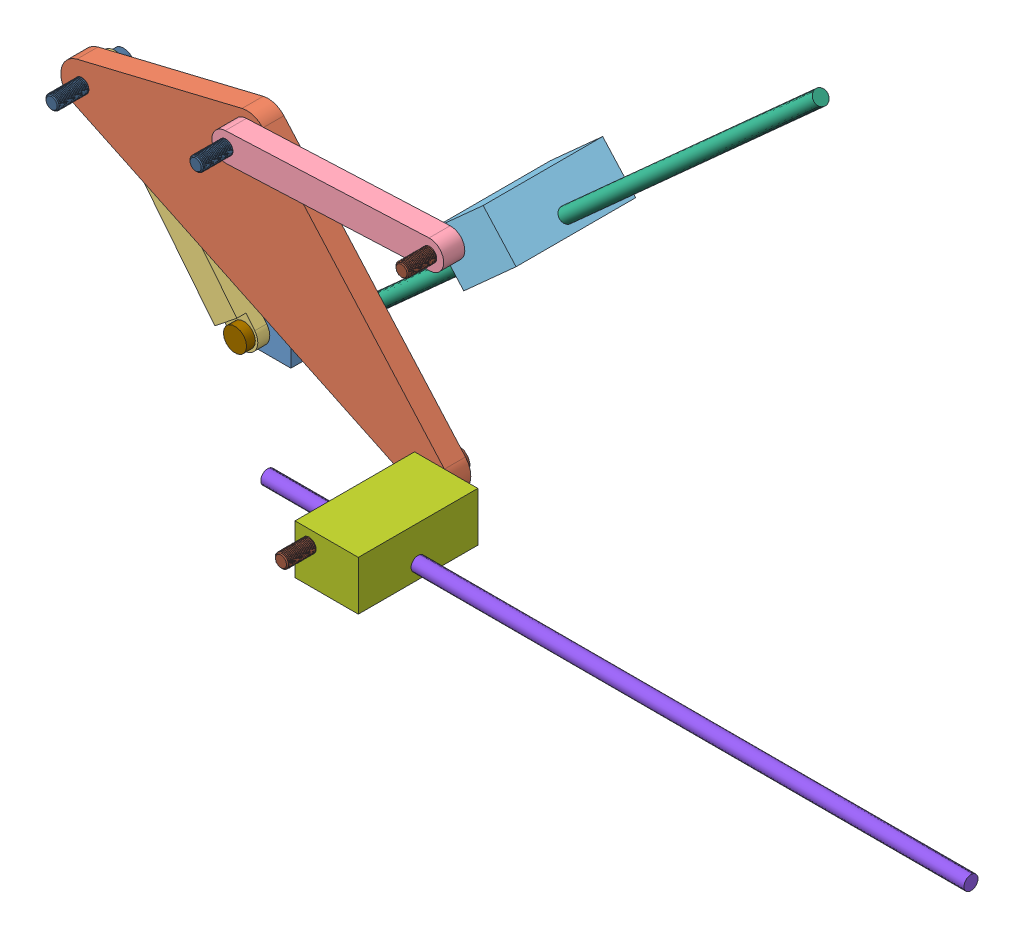
SolidWorks assembly sapr_5_Сборочная_деталь_1, configuration По умолчанию. Lengths in mm.
Overall size (1389.38 752.11 392.5).
13 component instances, 11 part files, 35 mates.
Components (placement in the parent):
- sapr_5_стойка_A-1: sapr_5_стойка_A [По умолчанию] at origin size (80 50 50)
- sapr_5_тело_BDC-1: sapr_5_тело_BDC [По умолчанию] at (305.885 0 70) x (0.903167 -0.42929 0) z (0 0 1) size (606 212.06 30)
- sapr_5_кривошип_AB-1: sapr_5_кривошип_AB [По умолчанию] at (0 0 40) x (0.624147 -0.781307 0) z (0 0 1) size (340 40 30)
- sapr_5_шатун_DE-1: sapr_5_шатун_DE [По умолчанию] at (337.3495 303.7509 100) x (0.99905 0.043571 0) z (0 0 1) size (330 40 30)
- Деталь5^sapr_5_Сборочная_деталь_1-1: Деталь5^sapr_5_Сборочная_деталь_1 [По умолчанию] at (-28.4092 649.8427 85) x (-0.758571 -0.651591 0) z (0 0 -1) size (101.61 72.32 170) (virtual)
- Деталь6^sapr_5_Сборочная_деталь_1-1: Деталь6^sapr_5_Сборочная_деталь_1 [По умолчанию] at (663.8765 593.5874 42.8641) x (-0.194708 0.216245 -0.956727) z (0.743145 0.669131 0) size (20 20 870) (virtual)
- Деталь7^sapr_5_Сборочная_деталь_1-1: Деталь7^sapr_5_Сборочная_деталь_1 [По умолчанию] at (-6298.3923 -94.2281 85) x (0.921199 -0.389093 0) z (0 0 1) size (110.14 99.5 170) (virtual)
- Деталь1^sapr_5_Сборочная_деталь_1-1: Деталь1^sapr_5_Сборочная_деталь_1 [По умолчанию] at (762.1607 -94.2281 85) x (0 0 -1) z (1 0 0) size (20 20 1000) (virtual)
- sapr_5_болт_A-1: sapr_5_болт_A [По умолчанию] at (0 0 42) x (-0.923728 -0.383049 0) z (0 0 -1) size (33 33 122.5)
- sapr_5_болт_B_и_D-1: sapr_5_болт_B_и_D [По умолчанию] at (-187.2441 234.3921 38) size (33 33 102.5)
- sapr_5_болт_B_и_D-2: sapr_5_болт_B_и_D [По умолчанию] at (47.6249 291.1153 68) x (0.967831 0.251601 0) z (0 0 1) size (33 33 102.5)
- sapr_5_болт_C_и_E-1: sapr_5_болт_C_и_E [По умолчанию] at (337.3495 303.7509 -85) size (33 33 252.5)
- sapr_5_болт_C_и_E-2: sapr_5_болт_C_и_E [По умолчанию] at (305.885 0 55) x (0.841902 0.53963 0) z (0 0 1) size (33 33 252.5)
Mates (geometry in assembly coordinates):
- Совпадение3: coordinate: point of sapr_5_стойка_A-1; point of assembly
- Концентричный1: concentric aligned: cylinder of sapr_5_стойка_A-1 through (0 0 25) axis (0 0 -1) radius 10; cylinder of sapr_5_кривошип_AB-1 through (0 0 55) axis (0 0 -1) radius 10
- Совпадение4: coincident anti-aligned: plane of sapr_5_стойка_A-1 through (0 0 25) normal (0 0 1); plane of sapr_5_кривошип_AB-1 through (0 0 25) normal (0 0 -1)
- Концентричный2: concentric aligned: cylinder of sapr_5_тело_BDC-1 through (-187.2441 234.3921 85) axis (0 0 -1) radius 10; cylinder of sapr_5_кривошип_AB-1 through (-187.2441 234.3921 55) axis (0 0 -1) radius 10
- На месте4: in place: plane of ? through (491.4763 205.3087 60) normal (0 0 1); plane of ? through (0 0 60) normal (0 0 1); moOrthogonalPlaneRef_w of ? through (491.4763 205.3087 60) normal (0 0 1); plane of ? through (0 0 60) normal (0 1 0); plane of ? through (491.4763 205.3087 60) normal (0 0 1); plane of ? through (0 0 60) normal (1 0 0); plane of ? through (491.4763 205.3087 60) normal (0 0 1); unknown of ?
- Совпадение21: coincident aligned: plane of sapr_5_тело_BDC-1; plane of Деталь7^sapr_5_Сборочная_деталь_1-1
- Совпадение22: coincident aligned: moOrthogonalPlaneRef_w of sapr_5_тело_BDC-1 through (836.1365 24.5996 60) normal (0.081391 0.996682 0); plane of Деталь7^sapr_5_Сборочная_деталь_1-1
- Совпадение23: coincident anti-aligned: moOrthogonalPlaneRef_w of sapr_5_тело_BDC-1 through (836.1365 24.5996 60) normal (-0.996682 0.081391 0); plane of Деталь7^sapr_5_Сборочная_деталь_1-1
- Совпадение24: coincident anti-aligned: plane of sapr_5_тело_BDC-1 through (515.9638 141.815 60) normal (0 0 1); plane of Деталь7^sapr_5_Сборочная_деталь_1-1 through (827.9654 -90.7821 60) normal (0 0 -1)
- Параллельность1: parallel anti-aligned: line of ? through (907.5887 -21.6191 100) axis (-1 0 0)
- Концентричный11: concentric anti-aligned: cylinder of sapr_5_шатун_DE-1 through (337.3495 303.7509 115) axis (0 0 -1) radius 10; cylinder of Деталь5^sapr_5_Сборочная_деталь_1-1 through (337.3495 303.7509 -85) axis (0 0 1) radius 10
- Совпадение26: coincident anti-aligned: plane of sapr_5_тело_BDC-1 through (47.6249 291.1153 85) normal (0 0 1); plane of Деталь7^sapr_5_Сборочная_деталь_1-1 through (-6298.3923 -94.2281 85) normal (0 0 -1)
- На месте5: in place: plane of ? through (762.1607 -50 100) normal (1 0 0); plane of ? through (762.1607 0 0) normal (1 0 0); plane of ? through (762.1607 -50 100) normal (1 0 0); plane of ? through (762.1607 0 0) normal (0 1 0); plane of ? through (762.1607 -50 100) normal (1 0 0); plane of ? through (762.1607 0 0) normal (0 0 -1); plane of ? through (762.1607 -50 100) normal (1 0 0); unknown of ?
- Совпадение28: coincident aligned: plane of Деталь7^sapr_5_Сборочная_деталь_1-1; plane of Деталь1^sapr_5_Сборочная_деталь_1-1
- Совпадение29: coincident aligned: moOrthogonalPlaneRef_w of Деталь7^sapr_5_Сборочная_деталь_1-1 through (762.1607 -122.7583 60) normal (0 1 0); plane of Деталь1^sapr_5_Сборочная_деталь_1-1 through (762.1607 -122.7583 60) normal (0 1 0)
- Совпадение30: coincident anti-aligned: moOrthogonalPlaneRef_w of Деталь7^sapr_5_Сборочная_деталь_1-1 through (762.1607 -122.7583 60) normal (0 0 1); plane of Деталь1^sapr_5_Сборочная_деталь_1-1 through (762.1607 -122.7583 60) normal (0 0 -1)
- Параллельность2: parallel aligned: cylinder of Деталь1^sapr_5_Сборочная_деталь_1-1 through (162.1607 -30 170) axis (1 0 0) radius 10; line of assembly
- Параллельность3: parallel aligned: cylinder of Деталь1^sapr_5_Сборочная_деталь_1-1 through (162.1607 -30 170) axis (1 0 0) radius 10; line of assembly
- Концентричный12: concentric aligned: cylinder of Деталь7^sapr_5_Сборочная_деталь_1-1 through (260.7935 -30 170) axis (1 0 0) radius 10; cylinder of Деталь1^sapr_5_Сборочная_деталь_1-1 through (162.1607 -30 170) axis (1 0 0) radius 10
- Концентричный13: concentric aligned: cylinder of sapr_5_тело_BDC-1 through (305.885 0 85) axis (0 0 -1) radius 10; cylinder of Деталь7^sapr_5_Сборочная_деталь_1-1 through (305.885 0 255) axis (0 0 -1) radius 10
- Концентричный14: concentric aligned: cylinder of sapr_5_тело_BDC-1 through (47.6249 291.1153 85) axis (0 0 -1) radius 10; cylinder of sapr_5_шатун_DE-1 through (47.6249 291.1153 115) axis (0 0 -1) radius 10
- Совпадение31: coincident anti-aligned: plane of sapr_5_тело_BDC-1 through (47.6249 291.1153 85) normal (0 0 1); plane of sapr_5_шатун_DE-1 through (337.3495 303.7509 85) normal (0 0 -1)
- Совпадение32: coincident anti-aligned: plane of sapr_5_шатун_DE-1 through (337.3495 303.7509 85) normal (0 0 -1); plane of Деталь5^sapr_5_Сборочная_деталь_1-1 through (-28.4092 649.8427 85) normal (0 0 1)
- Концентричный15: concentric anti-aligned: cylinder of sapr_5_кривошип_AB-1 through (0 0 55) axis (0 0 -1) radius 10; cylinder of sapr_5_болт_A-1 through (0 0 -68) axis (0 0 1) radius 10
- Совпадение34: coincident anti-aligned: plane of sapr_5_кривошип_AB-1 through (0 0 42) normal (0 0 1); plane of sapr_5_болт_A-1 through (0 0 42) normal (0 0 -1)
- Совпадение35: coincident anti-aligned: plane of sapr_5_тело_BDC-1 through (47.6249 291.1153 55) normal (0 0 -1); plane of sapr_5_кривошип_AB-1 through (0 0 55) normal (0 0 1)
- Концентричный16: concentric aligned: cylinder of sapr_5_кривошип_AB-1 through (-187.2441 234.3921 55) axis (0 0 -1) radius 10; cylinder of sapr_5_болт_B_и_D-1 through (-187.2441 234.3921 128) axis (0 0 -1) radius 10
- Совпадение36: coincident anti-aligned: plane of sapr_5_кривошип_AB-1 through (0 0 38) normal (0 0 -1); plane of sapr_5_болт_B_и_D-1 through (-187.2441 234.3921 38) normal (0 0 1)
- Концентричный17: concentric aligned: cylinder of sapr_5_шатун_DE-1 through (47.6249 291.1153 115) axis (0 0 -1) radius 10; cylinder of sapr_5_болт_B_и_D-2 through (47.6249 291.1153 158) axis (0 0 -1) radius 10
- Совпадение37: coincident anti-aligned: plane of sapr_5_тело_BDC-1 through (47.6249 291.1153 68) normal (0 0 -1); plane of sapr_5_болт_B_и_D-2 through (47.6249 291.1153 68) normal (0 0 1)
- Концентричный18: concentric anti-aligned: cylinder of Деталь5^sapr_5_Сборочная_деталь_1-1 through (341.3451 266.9795 0) axis (0.743145 0.669131 0) radius 10; cylinder of Деталь6^sapr_5_Сборочная_деталь_1-1 through (778.4858 660.5828 0) axis (-0.743145 -0.669131 0) radius 10
- Концентричный19: concentric anti-aligned: cylinder of Деталь5^sapr_5_Сборочная_деталь_1-1 through (337.3495 303.7509 -85) axis (0 0 1) radius 10; cylinder of sapr_5_болт_C_и_E-1 through (337.3495 303.7509 155) axis (0 0 -1) radius 10
- Совпадение38: coincident anti-aligned: plane of Деталь5^sapr_5_Сборочная_деталь_1-1 through (-28.4092 649.8427 -85) normal (0 0 -1); plane of sapr_5_болт_C_и_E-1 through (337.3495 303.7509 -85) normal (0 0 1)
- Концентричный20: concentric aligned: cylinder of Деталь7^sapr_5_Сборочная_деталь_1-1 through (305.885 0 255) axis (0 0 -1) radius 10; cylinder of sapr_5_болт_C_и_E-2 through (305.885 0 295) axis (0 0 -1) radius 10
- Совпадение39: coincident anti-aligned: plane of sapr_5_тело_BDC-1 through (47.6249 291.1153 55) normal (0 0 -1); plane of sapr_5_болт_C_и_E-2 through (305.885 0 55) normal (0 0 1)
